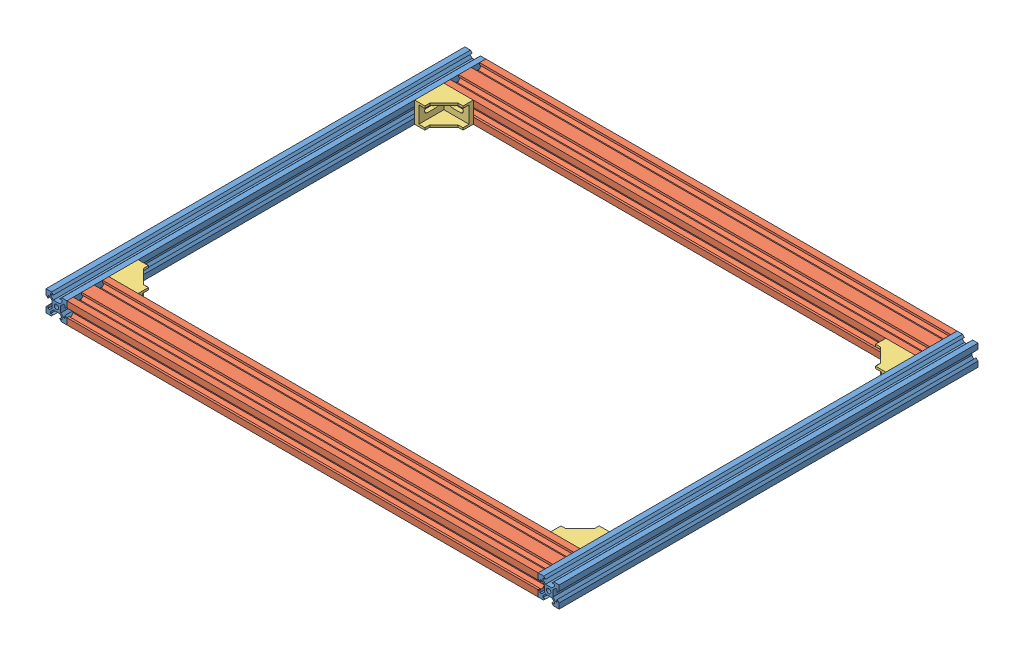
SolidWorks assembly Quadrado_400x490mm, configuration Valor predeterminado. Lengths in mm.
Overall size (490 20 400).
8 component instances, 3 part files, 12 mates.
Components (placement in the parent):
- Perfil_20x20mm-3: Perfil_20x20mm [400mm] at (-555.9529 400 -177.9915) x (1 0 0) z (0 -1 0) size (20 400 20)
- Perfil_20x40mm-2: Perfil_20x40mm [450mm] at (-545.9529 400 -147.9915) x (0 0 -1) z (0 -1 0) size (40 450 20)
- Perfil_20x40mm-3: Perfil_20x40mm [450mm] at (-545.9529 400 212.0085) x (0 0 -1) z (0 -1 0) size (40 450 20)
- Perfil_20x20mm-4: Perfil_20x20mm [400mm] at (-85.9529 400 -177.9915) x (1 0 0) z (0 -1 0) size (20 400 20)
- Cantoneira_interna_20x20mm-1: Cantoneira_interna_20x20mm [Default] at (-95.9529 390 182.0085) x (0 1 0) z (0 0 1) size (20 28 28)
- Cantoneira_interna_20x20mm-2: Cantoneira_interna_20x20mm [Default] at (-95.9529 410 -137.9915) x (0 -1 0) z (0 0 -1) size (20 28 28)
- Cantoneira_interna_20x20mm-3: Cantoneira_interna_20x20mm [Default] at (-545.9529 390 -137.9915) x (0 1 0) z (0 0 -1) size (20 28 28)
- Cantoneira_interna_20x20mm-4: Cantoneira_interna_20x20mm [Default] at (-545.9529 410 182.0085) x (0 -1 0) z (0 0 1) size (20 28 28)
Mates (geometry in assembly coordinates):
- Coincidente1: coincident aligned: plane of Perfil_20x40mm-3 through (-95.9529 410 222.0085) normal (0 0 1); plane of Perfil_20x20mm-4 through (-85.9529 400 222.0085) normal (0 0 1)
- Coincidente2: coincident anti-aligned: plane of Perfil_20x40mm-3 through (-95.9529 400 212.0085) normal (1 0 0); plane of Perfil_20x20mm-4 through (-95.9529 400 222.0085) normal (-1 0 0)
- Coincidente3: coincident aligned: plane of Perfil_20x40mm-3 through (-95.9529 410 222.0085) normal (0 1 0); plane of Perfil_20x20mm-4 through (-85.9529 410 222.0085) normal (0 1 0)
- Coincidente4: coincident aligned: plane of Perfil_20x20mm-3 through (-555.9529 410 222.0085) normal (0 1 0); plane of Perfil_20x40mm-3 through (-95.9529 410 222.0085) normal (0 1 0)
- Coincidente5: coincident aligned: plane of Perfil_20x20mm-3 through (-555.9529 400 222.0085) normal (0 0 1); plane of Perfil_20x40mm-3 through (-95.9529 396 222.0085) normal (0 0 1)
- Coincidente6: coincident anti-aligned: plane of Perfil_20x20mm-3 through (-545.9529 400 222.0085) normal (1 0 0); plane of Perfil_20x40mm-3 through (-545.9529 400 212.0085) normal (-1 0 0)
- Coincidente7: coincident aligned: plane of Perfil_20x20mm-3 through (-555.9529 410 222.0085) normal (0 1 0); plane of Perfil_20x40mm-2 through (-95.9529 410 -177.9915) normal (0 1 0)
- Coincidente8: coincident anti-aligned: plane of Perfil_20x20mm-3 through (-545.9529 400 222.0085) normal (1 0 0); plane of Perfil_20x40mm-2 through (-545.9529 400 -147.9915) normal (-1 0 0)
- Coincidente9: coincident aligned: plane of Perfil_20x20mm-3 through (-555.9529 400 -177.9915) normal (0 0 -1); plane of Perfil_20x40mm-2 through (-95.9529 410 -177.9915) normal (0 0 -1)
- Coincidente10: coincident aligned: plane of Perfil_20x40mm-3 through (-95.9529 410 182.0085) normal (0 1 0); plane of Cantoneira_interna_20x20mm-1 through (-95.9529 410 182.0085) normal (0 1 0)
- Coincidente11: coincident anti-aligned: plane of Perfil_20x20mm-4 through (-95.9529 400 222.0085) normal (-1 0 0); plane of Cantoneira_interna_20x20mm-1 through (-95.9529 410 182.0085) normal (1 0 0)
- Coincidente12: coincident anti-aligned: plane of Perfil_20x40mm-3 through (-95.9529 410 182.0085) normal (0 0 -1); plane of Cantoneira_interna_20x20mm-1 through (-95.9529 410 182.0085) normal (0 0 1)
